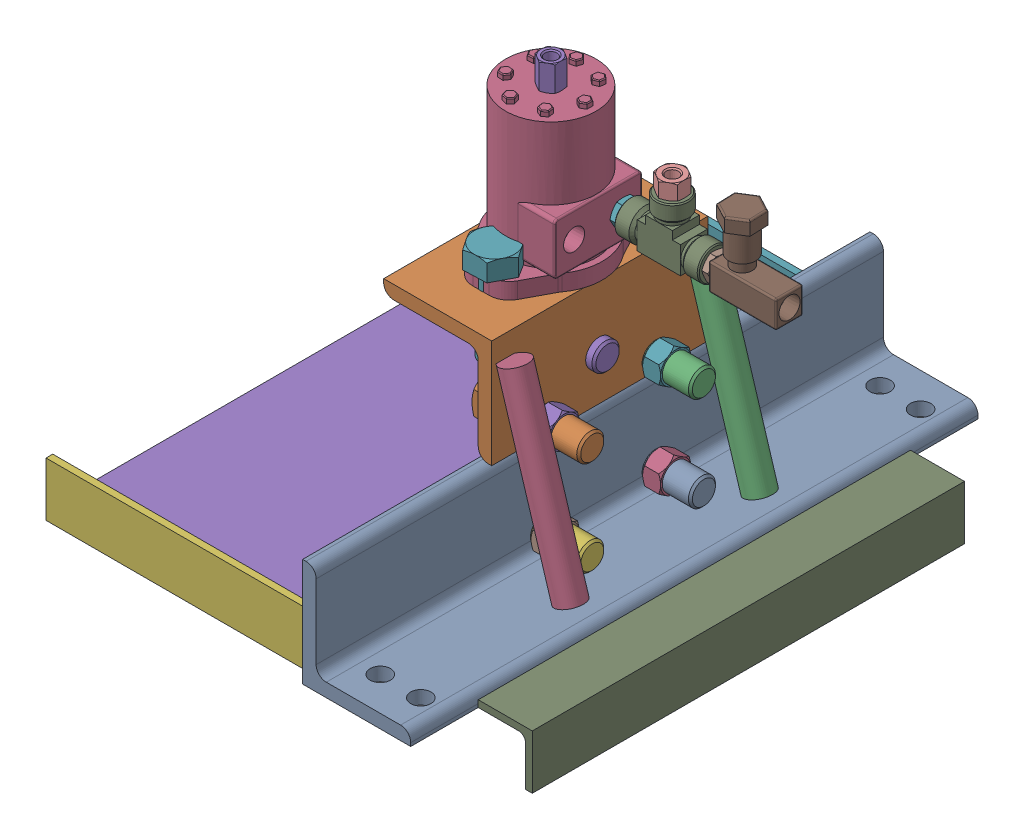
SolidWorks assembly 01-076-00-0, configuration Default. Lengths in mm.
Overall size (422.22 406.65 533.4).
48 component instances, 21 part files, 0 mates.
Components (placement in the parent):
- 01-048-00-0-1: 01-048-00-0 [Default] at (-161.4838 -113.0009 54.5674) size (406.4 247.65 533.4)
  - 01-042-00-0-1: 01-042-00-0 [Default] at origin size (101.6 101.6 533.4)
  - 01-043-00-0-1: 01-043-00-0 [Default] at (12.7 203.2 0) x (-1 0 0) z (0 0 1) size (101.6 101.6 203.2)
  - 01-047-00-0-1: 01-047-00-0 [Default] at (74.1068 15.97 -88.9) x (0.948496 0.291905 -0.123074) z (0.11763 0.036201 0.992397) size (25.4 177.8 25.4)
  - 01-047-00-0-2: 01-047-00-0 [Default] at (74.1066 15.5263 89.0193) x (0.948496 0.291905 -0.123074) z (0.11763 0.036201 0.992397) size (25.4 177.8 25.4)
  - 01-074-00-0-1: 01-074-00-0 [Default] at (0 6.35 241.3) x (0 0 -1) z (1 0 0) size (482.6 3.17 254)
  - 01-105-00-0-1: 01-105-00-0 [Default] at (-127 0 254) x (0 0 -1) z (1 0 0) size (50.8 50.8 254)
  - 01-105-00-0-2: 01-105-00-0 [Default] at (-127 0 -254) x (0 1 0) z (1 0 0) size (50.8 50.8 254)
  - 01-106-00-0-1: 01-106-00-0 [Default] at (-254 6.35 0) x (0 -1 0) z (0 0 1) size (50.8 50.8 406.4)
  - 01-106-00-0-2: 01-106-00-0 [Default] at (152.4 6.35 0) x (-1 0 0) z (0 0 1) size (50.8 50.8 406.4)
- 01-077-00-0-1: 01-077-00-0 [Default] at (-220.4962 -153.8949 79.6504) x (0.999923 0 0.012402) z (-0.012402 0 0.999923) size (177.8 190.5 152.4)
  - 01-044-00-0-1: 01-044-00-0 [Default] at origin size (127 25.4 50.8)
  - 01-045-00-0-1: 01-045-00-0 [Default] at (177.8 0 50.8) x (0 0 -1) z (1 0 0) size (152.4 25.4 50.8)
  - 01-046-00-0-1: 01-046-00-0 [Default] at (25.4 6.35 -25.4) size (25.4 184.15 25.4)
- hex bolt_ai(PreviewCfg)-1: hex bolt_ai(PreviewCfg) [Default] at (-197.374 -87.6009 2.0783) size (93.98 43.99 38.1)
- hex bolt_ai(PreviewCfg)-2: hex bolt_ai(PreviewCfg) [Default] at (-197.374 1.2991 107.0565) size (93.98 43.99 38.1)
- hex bolt_ai(PreviewCfg)-3: hex bolt_ai(PreviewCfg) [Default] at (-197.374 1.2991 2.0783) size (93.98 43.99 38.1)
- hex bolt_ai(PreviewCfg)-4: hex bolt_ai(PreviewCfg) [Default] at (-194.7832 123.2191 1.3544) x (0 -1 0) z (0.883967 0 0.467549) size (93.98 43.99 38.1)
- hex bolt_ai(PreviewCfg)-5: hex bolt_ai(PreviewCfg) [Default] at (-234.7851 30.2551 54.0712) x (0.999923 0 0.012402) z (0.002836 0.973504 -0.228653) size (93.98 43.99 38.1)
- hex bolt_ai(PreviewCfg)-6: hex bolt_ai(PreviewCfg) [Default] at (-197.374 -87.6009 107.0565) size (93.98 43.99 38.1)
- hex bolt_ai(PreviewCfg)-7: hex bolt_ai(PreviewCfg) [Default] at (-194.7832 123.2191 107.7804) x (0 -1 0) z (0.883967 0 0.467549) size (93.98 43.99 38.1)
- WASHER 0.375-WIDE-1: WASHER 0.375-WIDE [Default] at (-146.6756 1.2991 2.0783) size (2.11 25.4 25.4)
- WASHER 0.375-WIDE-2: WASHER 0.375-WIDE [Default] at (-177.4858 1.2991 2.0783) size (2.11 25.4 25.4)
- WASHER 0.375-WIDE-3: WASHER 0.375-WIDE [Default] at (-177.4858 -87.6009 107.0565) size (2.11 25.4 25.4)
- WASHER 0.375-WIDE-4: WASHER 0.375-WIDE [Default] at (-146.6756 -87.6009 107.0565) size (2.11 25.4 25.4)
- WASHER 0.375-WIDE-5: WASHER 0.375-WIDE [Default] at (-146.6756 -87.6009 2.0783) size (2.11 25.4 25.4)
- WASHER 0.375-WIDE-6: WASHER 0.375-WIDE [Default] at (-177.4858 -87.6009 2.0783) size (2.11 25.4 25.4)
- WASHER 0.375-WIDE-7: WASHER 0.375-WIDE [Default] at (-146.6756 1.2991 107.0565) size (2.11 25.4 25.4)
- WASHER 0.375-WIDE-8: WASHER 0.375-WIDE [Default] at (-177.4858 1.2991 107.0565) size (2.11 25.4 25.4)
- BMPH50H2KP-1: BMPH50H2KP [Default] at (-194.7832 90.1991 54.5674) x (0 0 -1) z (-1 0 0) size (131.32 192.98 96.77)
- SS-4-SAE-7_4-1: SS-4-SAE-7_4 [Default] at (-194.7832 215.6751 54.5674) x (0 1 0) z (0 0 1) size (33.53 19.05 22)
- Male Hex Nipple, NPT_SS-8-HN_1_2-1: Male Hex Nipple, NPT_SS-8-HN_1_2 [Default] at (-123.1933 132.8711 31.7074) x (-1 0 0) z (0 0 -1) size (46.74 22.23 25.66)
- Male Hex Nipple, NPT_SS-8-HN_1_2-2: Male Hex Nipple, NPT_SS-8-HN_1_2 [Default] at (-36.9095 132.8711 31.7074) x (-1 0 0) z (0 -0.924225 -0.381849) size (46.74 22.23 25.66)
- SS-8-T_3-1: SS-8-T_3 [Default] at (-63.7954 132.8711 31.7074) x (-1 0 0) z (0 -1 0) size (79.25 30.48 54.86)
- SS-8-RB-4-1: SS-8-RB-4 [Default] at (-103.4194 159.7951 31.7074) x (0 1 0) z (0 0 1) size (27.43 22.23 25.66)
- Control Valve - 0.5NPTF-1: Control Valve - 0.5NPTF [Default] at (6.7404 120.1711 19.0074) x (0 0 1) z (-1 0 0) size (34.87 73.03 63.5)
- flat washer type a wide_ai(PreviewCfg)-1: flat washer type a wide_ai(PreviewCfg) [Default] at (-194.7832 77.4991 1.3544) x (0 1 0) z (0 0 1) size (4.19 63.5 63.5)
- flat washer type a wide_ai(PreviewCfg)-2: flat washer type a wide_ai(PreviewCfg) [Default] at (-194.7832 77.4991 107.7804) x (0 1 0) z (0 0 1) size (4.19 63.5 63.5)
- hex nut_ai(PreviewCfg)-1: hex nut_ai(PreviewCfg) [Default] at (-172.5599 30.2551 54.843) x (-0.012135 0.206523 0.978366) z (-0.999923 0 -0.012402) size (28.57 33 16.89)
- hex nut_ai(PreviewCfg)-2: hex nut_ai(PreviewCfg) [Default] at (-194.7832 56.4171 1.3544) x (0.996756 0 0.080478) z (0 -1 0) size (28.57 33 16.89)
- hex nut_ai(PreviewCfg)-3: hex nut_ai(PreviewCfg) [Default] at (-146.6756 -87.6009 2.0783) x (0 0 1) z (-1 0 0) size (28.57 33 16.89)
- hex nut_ai(PreviewCfg)-4: hex nut_ai(PreviewCfg) [Default] at (-146.6756 1.2991 107.0565) x (0 0 1) z (-1 0 0) size (28.57 33 16.89)
- hex nut_ai(PreviewCfg)-5: hex nut_ai(PreviewCfg) [Default] at (-194.7832 56.4171 107.7804) x (0.996756 0 0.080478) z (0 -1 0) size (28.57 33 16.89)
- hex nut_ai(PreviewCfg)-6: hex nut_ai(PreviewCfg) [Default] at (-146.6756 1.2991 2.0783) x (0 0 1) z (-1 0 0) size (28.57 33 16.89)
- hex nut_ai(PreviewCfg)-7: hex nut_ai(PreviewCfg) [Default] at (-146.6756 -87.6009 107.0565) x (0 0 1) z (-1 0 0) size (28.57 33 16.89)
- 01-078-00-0-1: 01-078-00-0 [Default] at (-161.4838 -68.6017 124.5698) x (0 0 -1) z (0 1 0) size (140 67.2 38)
- 01-078-00-0-2: 01-078-00-0 [Default] at (-161.4838 20.2983 124.5698) x (0 0 -1) z (0 1 0) size (140 67.2 38)
- 01-085-00-0-1: 01-085-00-0 [Default] at (-194.7832 20.7301 54.5674) x (-0.012402 0 0.999923) z (-0.999923 0 -0.012402) size (44.45 50.8 44.45)
